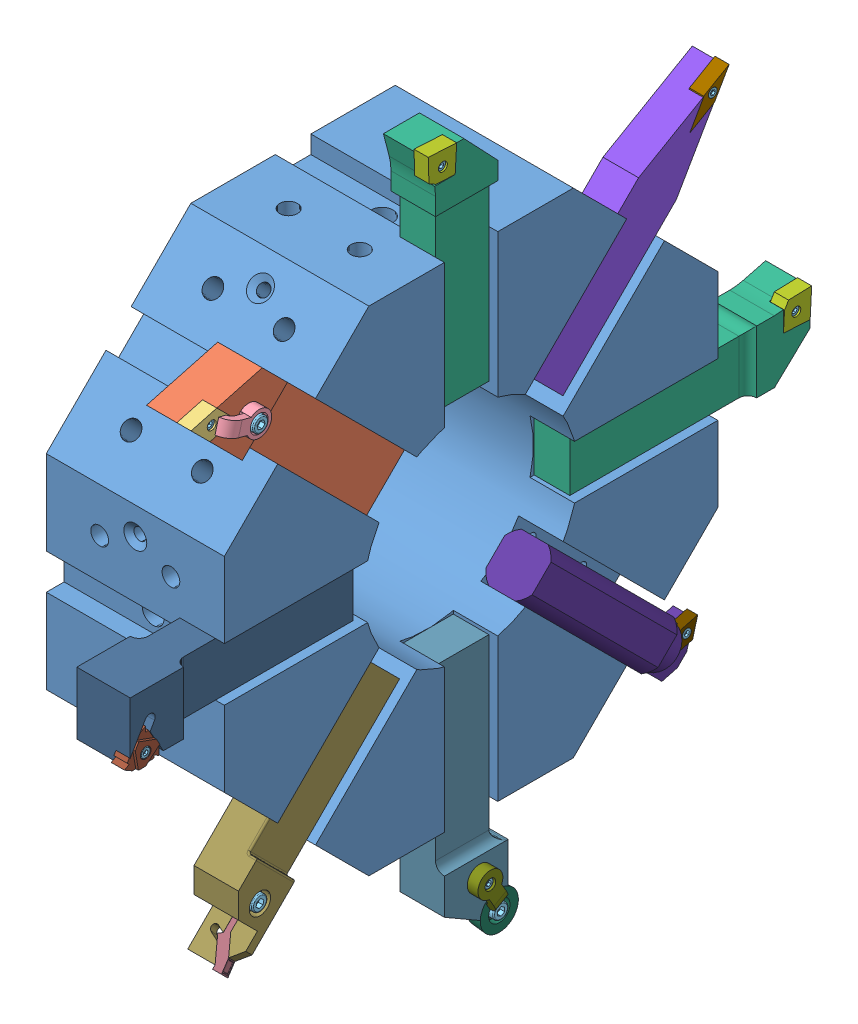
SolidWorks assembly 装配体1, configuration 默认. Lengths in mm.
Overall size (107 400.18 389.18).
37 component instances, 18 part files, 16 mates.
Components (placement in the parent):
- 转盘-1: 转盘 [默认] at (-40.074 7.4445 277.1639) size (100 277.16 277.16)
- 60度偏刀-1: 60度偏刀 [默认] at (34.926 103.1658 369.0963) x (0 0.707107 0.707107) z (1 0 0) size (144.45 42.34 32)
  - 60偏刀刀柄-1: 60偏刀刀柄 [默认] at (-21.8126 2.6791 0) size (140.7 35.85 25)
  - 60度偏刀刀片-2: 60度偏刀刀片 [默认] at (57.6325 17.0289 17) x (0.866025 0.5 0) z (0 0 1) size (25.98 15 8)
  - 60度偏刀挡片-1: 60度偏刀挡片 [默认] at (42.3835 13.9882 31) x (0.866025 0.5 0) z (0.5 -0.866025 0) size (25.45 12 14)
  - hexagon socket head cap screws gb2-3: hexagon socket head cap screws gb2 [GB_FASTENER_SCREWS_HSHCS M3X5-N] at (58.5069 17.5337 24) x (0 0 -1) z (1 0 0) size (8 5.5 5.5)
  - hexagon socket head cap screws gb2-4: hexagon socket head cap screws gb2 [GB_FASTENER_SCREWS_HSHCS M5X8-N] at (39.1874 7.5241 32) x (0 0 -1) z (0 -1 0) size (13 8.5 8.5)
- 90度偏刀-1: 90度偏刀 [默认] at (54.926 140.0957 295.9427) x (0 1 0) z (-1 0 0) size (130.88 39.9 25)
  - 90度偏刀刀柄-1: 90度偏刀刀柄 [默认] at (-29.3025 18.7788 0) size (130 39.26 25)
  - 90度偏刀刀-4: 90度偏刀刀 [默认] at (72.5922 0.3262 3) x (-0.998463 -0.055431 0) z (0 0 -1) size (15 16 8)
  - hexagon socket head cap screws gb2-1: hexagon socket head cap screws gb2 [GB_FASTENER_SCREWS_HSHCS M3X5-N] at (52.9494 2.9461 -4) x (0 0 1) z (-1 0 0) size (8 5.5 5.5)
- 尖刀-1: 尖刀 [默认] at (44.926 96.205 198.6229) x (0 0.707107 -0.707107) z (-1 0 0) size (146.98 30 20)
  - 尖刀刀柄-1: 尖刀刀柄 [默认] at (-10.7101 7.2263 -10) size (145.98 30 20)
  - 尖刀刀片-2: 尖刀刀片 [默认] at (77.7707 7.2263 -10) size (32 8.57 8)
  - hexagon socket head cap screws gb2-1: hexagon socket head cap screws gb2 [GB_FASTENER_SCREWS_HSHCS M3X5-N] at (80.7707 7.2263 -10) x (0 0 1) z (-1 0 0) size (8 5.5 5.5)
- 螺纹刀-1: 螺纹刀 [默认] at (44.926 10.1754 400.0756) x (0 0 1) z (1 0 0) size (136.42 44.29 31)
  - 螺纹刀刀柄-1: 螺纹刀刀柄 [默认] at (-16.4578 2.7309 -10) size (130 35 30)
  - 螺纹刀刀片-4: 螺纹刀刀片 [默认] at (72.0821 -15.7156 7) x (0.5 -0.866025 0) z (0 0 1) size (19.33 17.99 9)
  - hexagon socket head cap screws gb2-1: hexagon socket head cap screws gb2 [GB_FASTENER_SCREWS_HSHCS M3X5-N] at (60.8427 17.7759 16) x (0 0 -1) z (1 0 0) size (8 5.5 5.5)
- 切断刀-2: 切断刀 [默认] at (47.426 -80.8733 348.4732) x (0 0.707107 -0.707107) z (1 0 0) size (139.16 30 29.87)
  - 切断刀刀柄-1: 切断刀刀柄 [默认] at (18.1542 12.0268 -12.5) size (135 30 25)
  - 切断刀刀片-3: 切断刀刀片 [默认] at (-84.6401 2.0268 7.8462) x (0.866025 0 0.5) z (0 -1 0) size (21.49 20.95 5)
  - hexagon socket head cap screws gb2-1: hexagon socket head cap screws gb2 [GB_FASTENER_SCREWS_HSHCS M5X8-N] at (-56.8458 10.0268 12.5) x (0 0 -1) z (0.056624 -0.998396 0) size (13 8.5 8.5)
- 球头车刀-1: 球头车刀 [默认] at (47.426 -180.2868 290.9491) x (0 -1 0) z (1 0 0) size (146.02 44.83 31)
  - 球头车刀刀柄-1: 球头车刀刀柄 [默认] at (-77.8026 13.7853 -12.5) size (137.77 35.85 25)
  - 球头车刀刀片-1: 球头车刀刀片 [默认] at (4.2323 29.6303 12.5) x (-0.923728 -0.383049 0) z (0 0 -1) size (21.4 21.4 8)
  - 球头车刀挡片-1: 球头车刀挡片 [默认] at (-13.6064 25.0944 18.5) x (0.866025 0.5 0) z (0.5 -0.866025 0) size (25.45 12 14)
  - hexagon socket head cap screws gb2-1: hexagon socket head cap screws gb2 [GB_FASTENER_SCREWS_HSHCS M3X5-N] at (-16.8026 18.6303 17.5) x (0 0 -1) z (1 0 0) size (8 5.5 5.5)
  - hexagon socket head cap screws gb2-2: hexagon socket head cap screws gb2 [GB_FASTENER_SCREWS_HSHCS M5X8-N] at (4.2323 29.6303 13.5) x (0 0 -1) z (1 0 0) size (13 8.5 8.5)
- 镗刀-1: 镗刀 [默认] at (45.0538 -77.6481 190.3057) x (0 0.707107 -0.707107) z (0 -0.707107 -0.707107) size (31.47 25.98 130)
  - 镗刀刀柄-1: 镗刀刀柄 [默认] at (-3.2581 2.8626 -65) size (29.74 25.98 130)
  - 镗刀刀片-2: 镗刀刀片 [默认] at (5.6946 -2.1374 57.4707) x (1 0 0) z (0 1 0) size (19.05 11 6)
  - hexagon socket head cap screws gb2-1: hexagon socket head cap screws gb2 [GB_FASTENER_SCREWS_HSHCS M3X5-N] at (6.6683 3.8626 57.4707) x (0 -1 0) z (0 0 1) size (8 5.5 5.5)
- 90度偏刀-3: 90度偏刀 [默认] at (54.926 26.2233 147.439) x (0 0 -1) z (-1 0 0) size (130.88 39.9 25)
  - 90度偏刀刀柄-1: 90度偏刀刀柄 [默认] at (-29.3025 18.7788 0) size (130 39.26 25)
  - 90度偏刀刀-4: 90度偏刀刀 [默认] at (72.5922 0.3262 3) x (-0.998463 -0.055431 0) z (0 0 -1) size (15 16 8)
  - hexagon socket head cap screws gb2-1: hexagon socket head cap screws gb2 [GB_FASTENER_SCREWS_HSHCS M3X5-N] at (52.9494 2.9461 -4) x (0 0 1) z (-1 0 0) size (8 5.5 5.5)
Mates (geometry in assembly coordinates):
- 重合1: coincident anti-aligned: plane of 转盘-1 through (34.926 -120.5318 127.9743) normal (1 0 0); plane of 60度偏刀-1/60偏刀刀柄-1 through (34.926 85.8475 355.5669) normal (-1 0 0)
- 重合2: coincident anti-aligned: plane of 转盘-1 through (59.926 -141.745 149.1875) normal (0 0.707107 -0.707107); plane of 60度偏刀-1/60偏刀刀柄-1 through (54.926 39.8856 330.8181) normal (0 -0.707107 0.707107)
- 重合3: coincident anti-aligned: plane of 转盘-1 through (34.926 -131.1384 262.1639) normal (1 0 0); plane of 90度偏刀-1/90度偏刀刀柄-1 through (34.926 110.7933 277.1639) normal (-1 0 0)
- 重合4: coincident anti-aligned: plane of 转盘-1 through (59.926 -131.1384 292.1639) normal (0 0 -1); plane of 90度偏刀-1/90度偏刀刀柄-1 through (34.926 70.7933 292.1639) normal (0 0 1)
- 重合5: coincident anti-aligned: plane of 转盘-1 through (34.926 -141.745 405.1402) normal (1 0 0); plane of 尖刀-1/尖刀刀柄-1 through (34.926 83.5221 201.0863) normal (-1 0 0)
- 重合6: coincident anti-aligned: plane of 转盘-1 through (59.926 -141.745 405.1402) normal (0 0.707107 0.707107); plane of 尖刀-1/尖刀刀柄-1 through (34.926 42.8634 220.5317) normal (0 -0.707107 -0.707107)
- 重合8: coincident anti-aligned: plane of 转盘-1 through (34.926 22.4445 138.5809) normal (1 0 0); plane of 螺纹刀-1/螺纹刀刀柄-1 through (34.926 7.4445 383.6178) normal (-1 0 0)
- 重合9: coincident anti-aligned: plane of 转盘-1 through (59.926 22.4445 138.5809) normal (0 -1 0); plane of 螺纹刀-1/螺纹刀刀柄-1 through (54.926 22.4445 338.6178) normal (0 1 0)
- 重合12: coincident anti-aligned: plane of 转盘-1 through (34.926 156.634 149.1875) normal (1 0 0); plane of 切断刀-2/切断刀刀柄-1 through (34.926 -59.5321 344.1405) normal (-1 0 0)
- 重合13: coincident anti-aligned: plane of 转盘-1 through (59.926 135.4208 127.9743) normal (0 0.707107 0.707107); plane of 切断刀-2/切断刀刀柄-1 through (54.926 -112.5651 375.9603) normal (0 -0.707107 -0.707107)
- 重合14: coincident anti-aligned: plane of 转盘-1 through (34.926 146.0274 292.1639) normal (1 0 0); plane of 球头车刀-1/球头车刀刀柄-1 through (34.926 -102.4842 277.1639) normal (-1 0 0)
- 重合15: coincident anti-aligned: plane of 转盘-1 through (59.926 146.0274 262.1639) normal (0 0 1); plane of 球头车刀-1/球头车刀刀柄-1 through (54.926 -52.4842 262.1639) normal (0 0 -1)
- 重合16: coincident anti-aligned: plane of 转盘-1 through (34.926 135.4208 426.3534) normal (1 0 0); plane of 镗刀-1/镗刀刀柄-1 through (34.926 -99.3973 162.5575) normal (-1 0 0)
- 重合17: coincident anti-aligned: plane of 转盘-1 through (59.926 135.4208 426.3534) normal (0 0.707107 -0.707107); plane of 镗刀-1/镗刀刀柄-1 through (55.4164 -113.8862 177.0464) normal (0 -0.707107 0.707107)
- 重合20: coincident anti-aligned: plane of 转盘-1 through (34.926 -7.5555 415.7468) normal (1 0 0); plane of 90度偏刀-3/90度偏刀刀柄-1 through (34.926 7.4445 176.7414) normal (-1 0 0)
- 重合21: coincident anti-aligned: plane of 转盘-1 through (59.926 -7.5555 415.7468) normal (0 1 0); plane of 90度偏刀-3/90度偏刀刀柄-1 through (34.926 -7.5555 216.7414) normal (0 -1 0)
